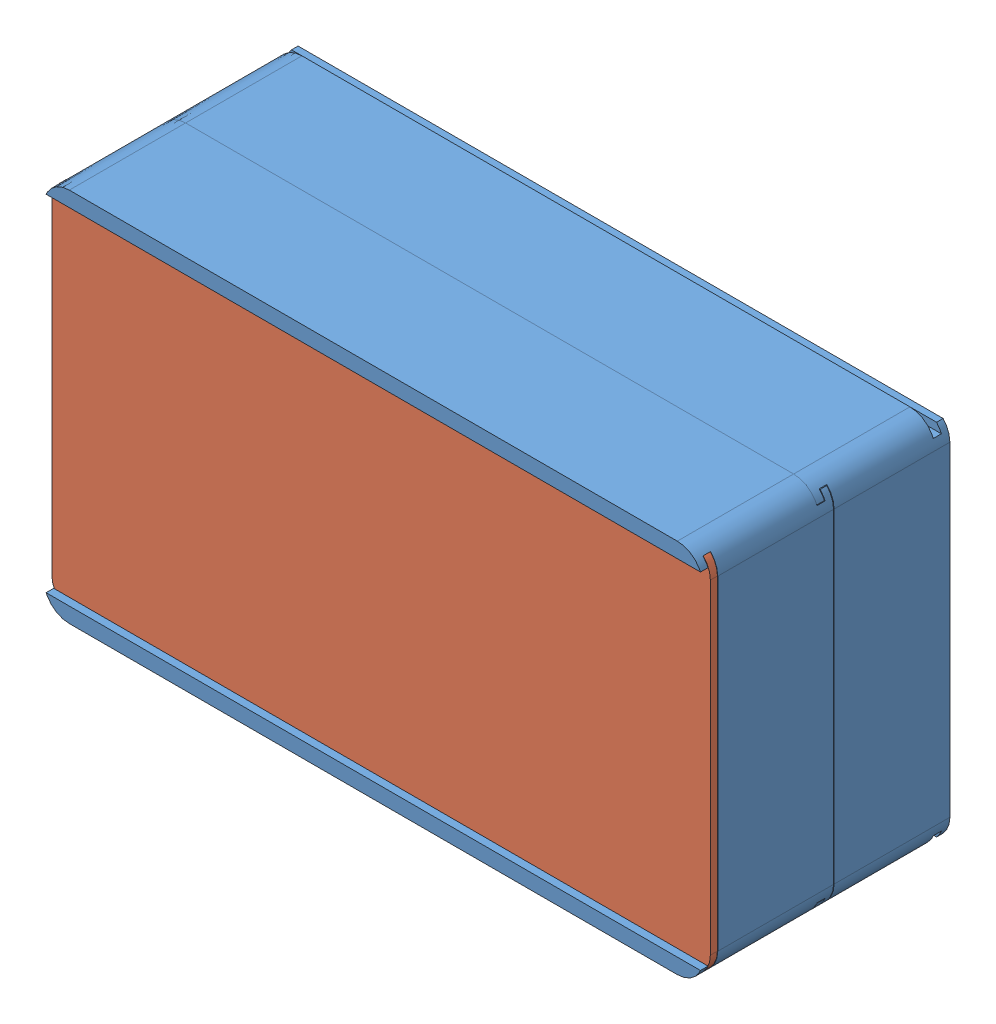
SolidWorks assembly EnsambleMuestra, configuration Predeterminado. Lengths in mm.
Overall size (130.31 74.24 48.9).
3 component instances, 2 part files, 4 mates.
Components (placement in the parent):
- CajaResistencias-1: CajaResistencias [Predeterminado] at (-108.5244 39.4762 130.2426) size (130.24 74.24 25.9)
- CajaResistencias-2: CajaResistencias [Predeterminado] at (-108.5311 39.4762 153.2426) size (130.24 74.24 25.9)
- TapaResistencias-1: TapaResistencias [Predeterminado] at (-110.7097 43.0948 173.2426) size (130.24 71.24 1.4)
Mates (geometry in assembly coordinates):
- Coincidente2: coincident anti-aligned: plane of CajaResistencias-1 through (-108.5244 39.4762 153.2426) normal (0 0 1); plane of CajaResistencias-2 through (-108.5311 39.4762 153.2426) normal (0 0 -1)
- Coincidente3: coincident aligned: plane of CajaResistencias-1 through (-110.6457 -29.6452 153.2426) normal (0 -1 0); plane of CajaResistencias-2 through (-110.6524 -29.6452 176.2426) normal (0 -1 0)
- Coincidente4: coincident anti-aligned: plane of CajaResistencias-2 through (19.5902 -28.1452 174.7426) normal (0 1 0); plane of TapaResistencias-1 through (-110.7097 -28.1452 174.6426) normal (0 -1 0)
- Coincidente5: coincident anti-aligned: plane of CajaResistencias-2 through (-108.5311 39.4762 173.2426) normal (0 0 1); plane of TapaResistencias-1 through (-110.7097 43.0948 173.2426) normal (0 0 -1)
